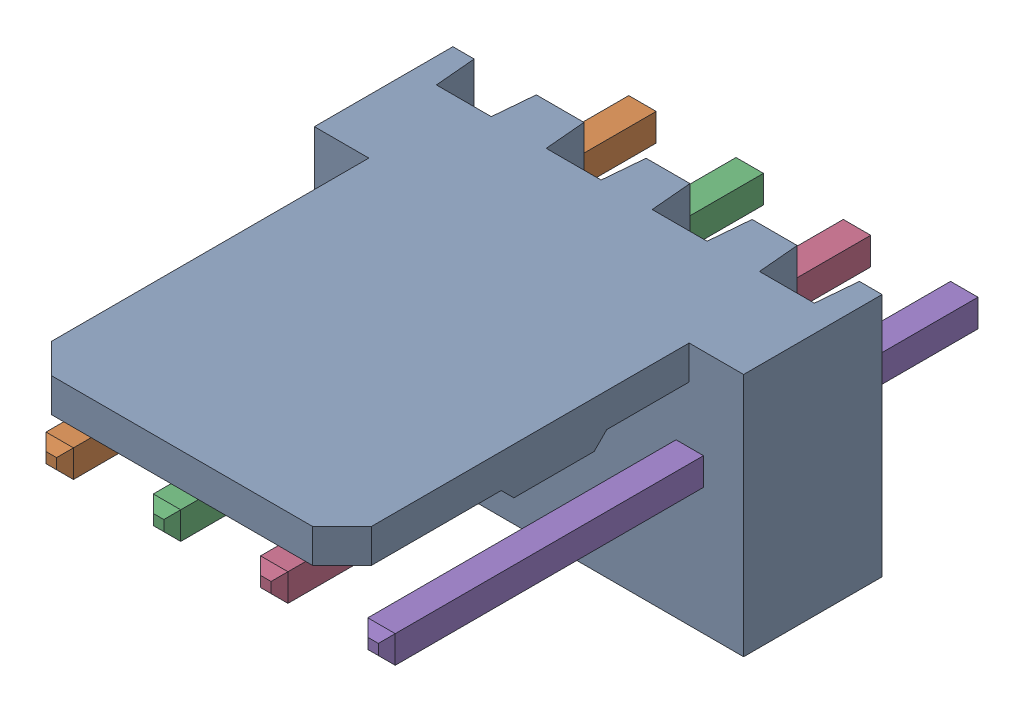
SolidWorks assembly Molex PCB 4 pin v3_7, configuration Default. Lengths in mm.
Overall size (10.16 5.79 14.92).
5 component instances, 2 part files, 0 mates.
Components (placement in the parent):
- BASE9710016-1: BASE9710016 [Default] at (2.54 2.895 -8.22) size (10.16 5.79 11.5)
- PINO9710016-1: PINO9710016 [Default] at (1.27 3.325 -0.72) size (0.65 0.65 14.2)
- PINO9710016-2: PINO9710016 [Default] at (3.81 3.325 -0.72) size (0.65 0.65 14.2)
- PINO9710016-3: PINO9710016 [Default] at (6.35 3.325 -0.72) size (0.65 0.65 14.2)
- PINO9710016-4: PINO9710016 [Default] at (8.89 3.325 -0.72) size (0.65 0.65 14.2)
